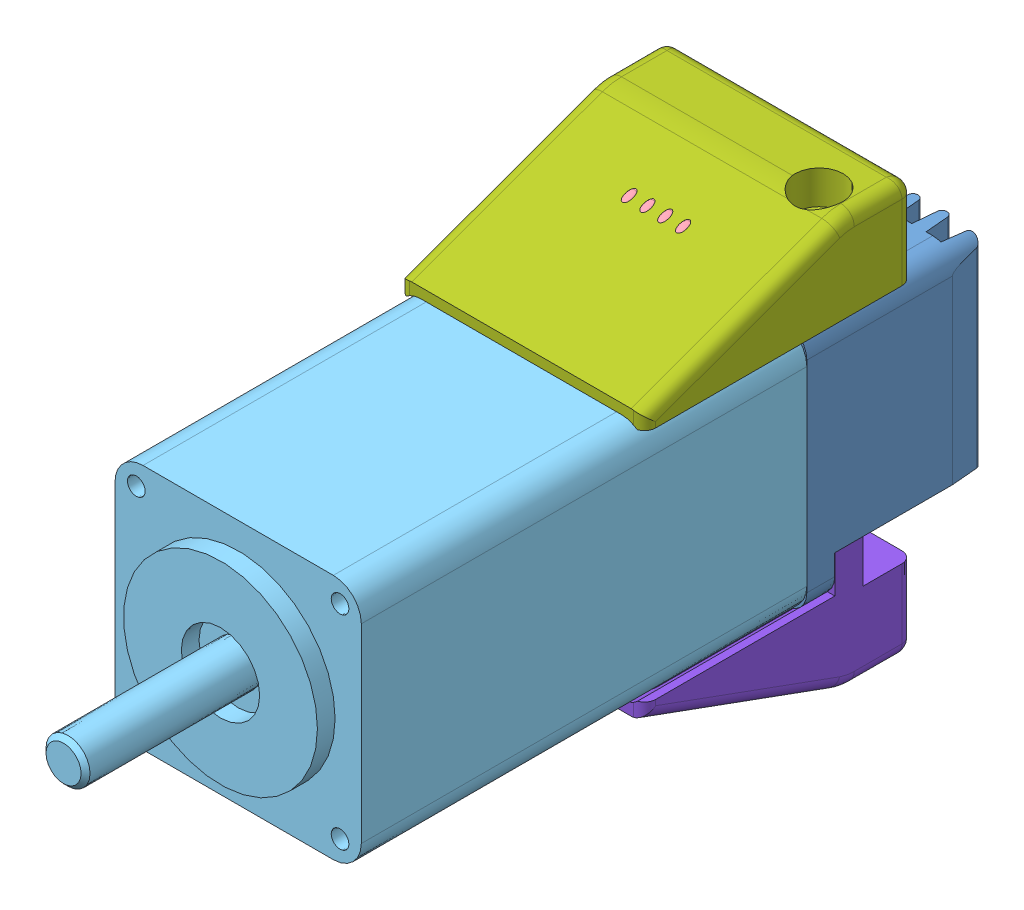
SolidWorks assembly DMX-K-DRV-11-3, configuration Default. Lengths in mm.
Overall size (27.99 46.74 90.36).
11 component instances, 8 part files, 0 mates.
Components (placement in the parent):
- DMX-K-DRV-11-ENC-1: DMX-K-DRV-11-ENC [Default] at (-8.4156 22.7026 -8.8637) x (0 -1 0) z (1 0 0) size (27.94 20.01 27.94)
- conn-housing-1: conn-housing [Default] at (6.5884 16.8126 -13.9034) x (1 0 0) z (0 1 0) size (10 5 8.89)
- connector-1: connector [Default] at (5.5945 24.2026 -15.1689) x (1 0 0) z (0 1 0) size (10 5 3.81)
- wiring-1: wiring [Default] at (6.5818 22.7026 -5.0602) x (-0.005296 0 -0.999986) z (0.999986 0 -0.005296) size (10.16 6.99 1.27)
- wiring-2: wiring [Default] at (4.5679 22.7026 -5.0595) x (-0.012779 0 -0.999918) z (0.999918 0 -0.012779) size (10.16 6.99 1.27)
- wiring-3: wiring [Default] at (2.5196 22.7026 -5.022) x (-0.003919 0 -0.999992) z (0.999992 0 -0.003919) size (10.16 6.99 1.27)
- wiring-4: wiring [Default] at (8.6197 22.7026 -5.0582) x (-0.008676 0 -0.999962) z (0.999962 0 -0.008676) size (10.16 6.99 1.27)
- Nema 11-20S Motor-1: Nema 11-20S Motor [Default] at (5.5544 8.7326 -8.8637) size (27.94 27.94 70.36)
- conn-housing-rear-1: conn-housing-rear [Default] at (5.6344 0.1526 -16.6041) x (1 0 0) z (0 -1 0) size (12 5 8.89)
- 100-108-1: 100-108 [Default] at (5.6814 16.8606 -5.6887) size (27.99 14.29 30.5)
- 100-109-1: 100-109 [Default] at (5.4274 0.6046 -5.6887) x (-1 0 0) z (0 0 1) size (27.99 14.29 30.5)
